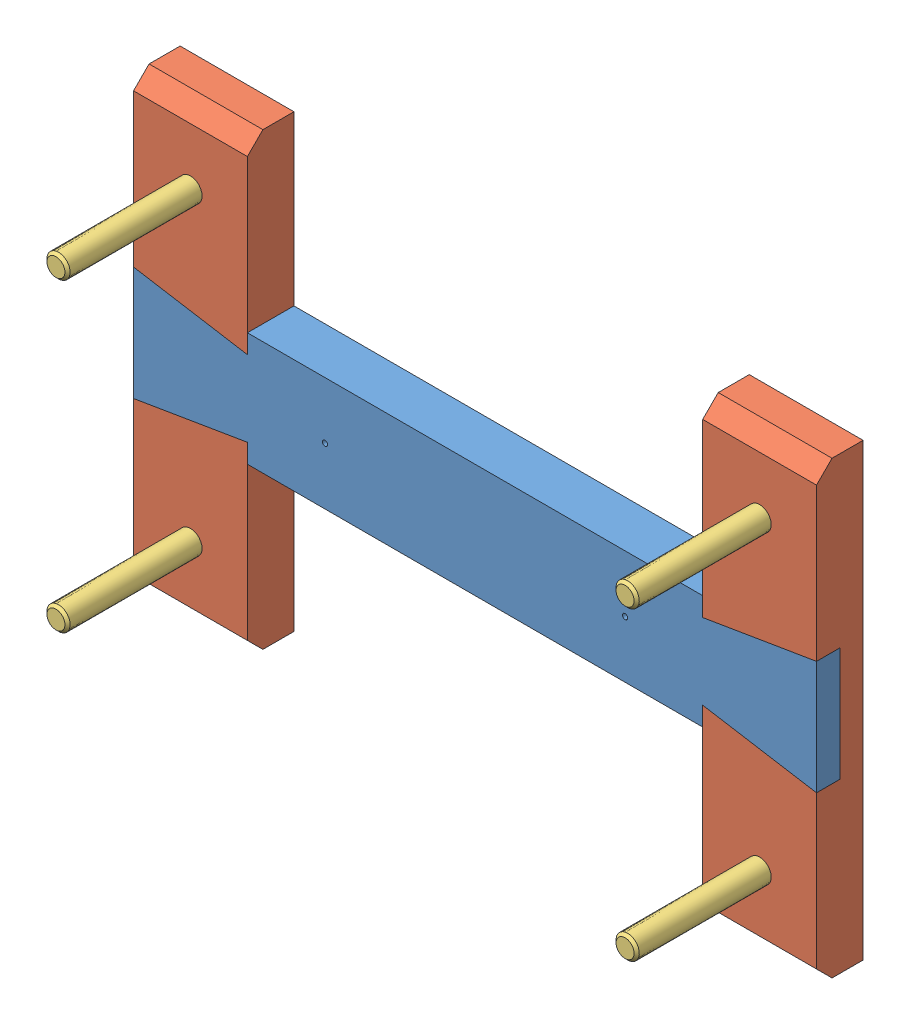
SolidWorks assembly Assem2, configuration Default. Lengths in mm.
Overall size (264 174 70).
7 component instances, 3 part files, 14 mates.
Components (placement in the parent):
- Main Body-1: Main Body [Default] at (5.2029 10.0368 -9.5643) size (264 44 18)
- Small Ends-1: Small Ends [Default] at (-104.7971 10.0368 -18.5643) x (1 0 0) z (0 -1 0) size (44 18 174)
- Small Ends-2: Small Ends [Default] at (115.2029 10.0368 -18.5643) x (-1 0 0) z (0 1 0) size (44 18 174)
- Dowel-1: Dowel [Default] at (115.2029 -48.9632 -18.5643) x (0.825731 -0.564065 0) z (-0.564065 -0.825731 0) size (9 70 9)
- Dowel-2: Dowel [Default] at (-104.7971 -48.9632 -18.5643) x (0.825731 -0.564065 0) z (-0.564065 -0.825731 0) size (9 70 9)
- Dowel-3: Dowel [Default] at (115.2029 69.0368 -18.5643) x (0.825731 -0.564065 0) z (-0.564065 -0.825731 0) size (9 70 9)
- Dowel-4: Dowel [Default] at (-104.7971 69.0368 -18.5643) x (0.825731 -0.564065 0) z (-0.564065 -0.825731 0) size (9 70 9)
Mates (geometry in assembly coordinates):
- Coincident1: coincident anti-aligned: plane of Main Body-1 through (-82.7971 -11.9632 -9.5643) normal (0 0 -1); plane of Small Ends-1 through (-82.7971 -4.6299 -9.5643) normal (0 0 1)
- Coincident2: coincident anti-aligned: line of Main Body-1 through (-126.7971 -11.9632 -9.5643) axis (0 1 0); line of Small Ends-1 through (-126.7971 32.0368 -9.5643) axis (0 -1 0)
- Coincident3: coincident aligned: line of Main Body-1 through (-126.7971 -11.9632 -0.5643) axis (0.986394 0.164399 0); line of Small Ends-1 through (-126.7971 -11.9632 -0.5643) axis (0.986394 0.164399 0)
- Coincident4: coincident anti-aligned: plane of Main Body-1 through (93.2029 -11.9632 -9.5643) normal (0 0 -1); plane of Small Ends-2 through (93.2029 24.7034 -9.5643) normal (0 0 1)
- Coincident5: coincident aligned: line of Main Body-1 through (137.2029 32.0368 -0.5643) axis (-0.986394 -0.164399 0); line of Small Ends-2 through (137.2029 32.0368 -0.5643) axis (-0.986394 -0.164399 0)
- Coincident6: coincident anti-aligned: line of Main Body-1 through (137.2029 32.0368 -9.5643) axis (0 -1 0); line of Small Ends-2 through (137.2029 -11.9632 -9.5643) axis (0 1 0)
- Coincident7: coincident aligned: plane of Dowel-1 through (115.2029 -48.9632 -18.5643) normal (0 0 -1); plane of Dowel-3 through (115.2029 69.0368 -18.5643) normal (0 0 -1)
- Coincident8: coincident aligned: plane of Dowel-1 through (115.2029 -48.9632 -18.5643) normal (0 0 -1); plane of Dowel-2 through (-104.7971 -48.9632 -18.5643) normal (0 0 -1)
- Coincident9: coincident aligned: plane of Dowel-1 through (115.2029 -48.9632 -18.5643) normal (0 0 -1); plane of Dowel-4 through (-204.5032 -157.9112 -18.5643) normal (0 0 -1)
- Coincident10: coincident aligned: plane of Dowel-1 through (115.2029 -48.9632 -18.5643) normal (0 0 -1); plane of Small Ends-2 through (137.2029 -76.9632 -18.5643) normal (0 0 -1)
- Coincident11: coincident aligned: circle of Small Ends-2; circle of Dowel-1
- Coincident12: coincident aligned: circle of Dowel-3; circle of Small Ends-2
- Coincident13: coincident aligned: circle of Small Ends-1; circle of Dowel-2
- Coincident14: coincident aligned: circle of Small Ends-1; circle of Dowel-4
